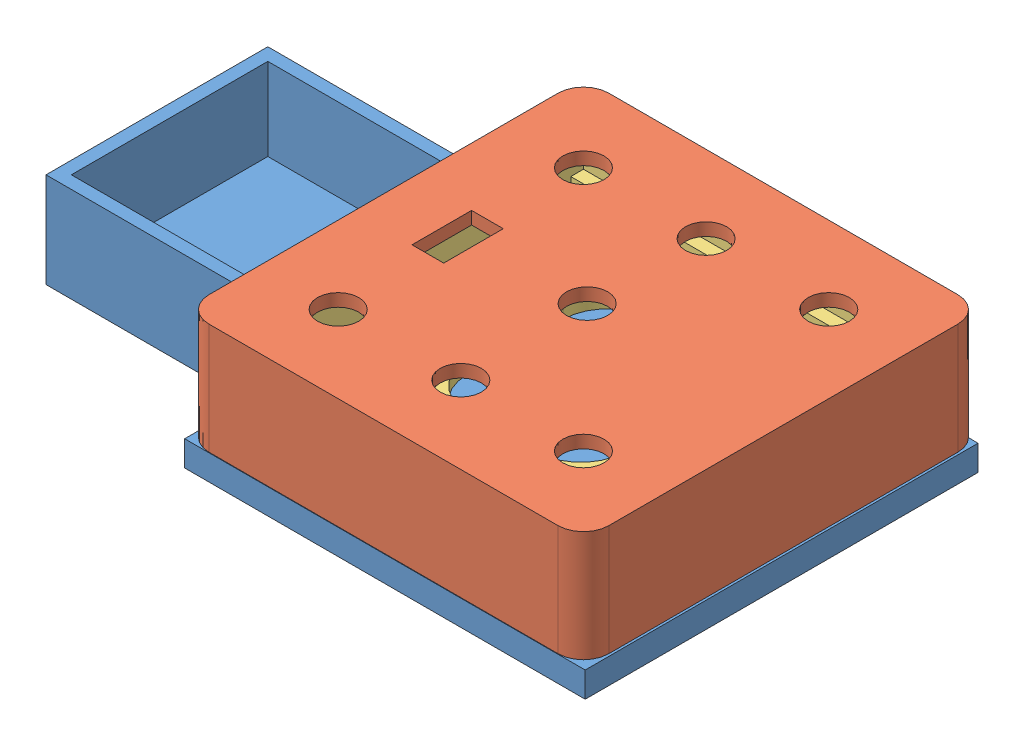
SolidWorks assembly Assem1, configuration Default. Lengths in mm.
Overall size (99.2 21.62 63.29).
3 component instances, 3 part files, 1 mates.
Components (placement in the parent):
- bunn-2-1: bunn-2 [Default] at (89.5802 58.9962 55.206) size (99.2 15 63.25)
- Part1-3-1: Part1-3 [Default] at (94.4981 78.6199 50.2333) x (1 0 0) z (0 0 -1) size (63.1 17.5 63.1)
- Part1-2-1: Part1-2 [Default] at (74.7657 65.6199 58.614) size (58.3 11 58.3)
Mates (geometry in assembly coordinates):
- ProfileCenter2: profile center anti-aligned: plane of Part1-2-1 through (74.7657 76.6199 58.614) normal (0 1 0); plane of Part1-3-1 through (94.4981 76.6199 50.2333) normal (0 -1 0)
